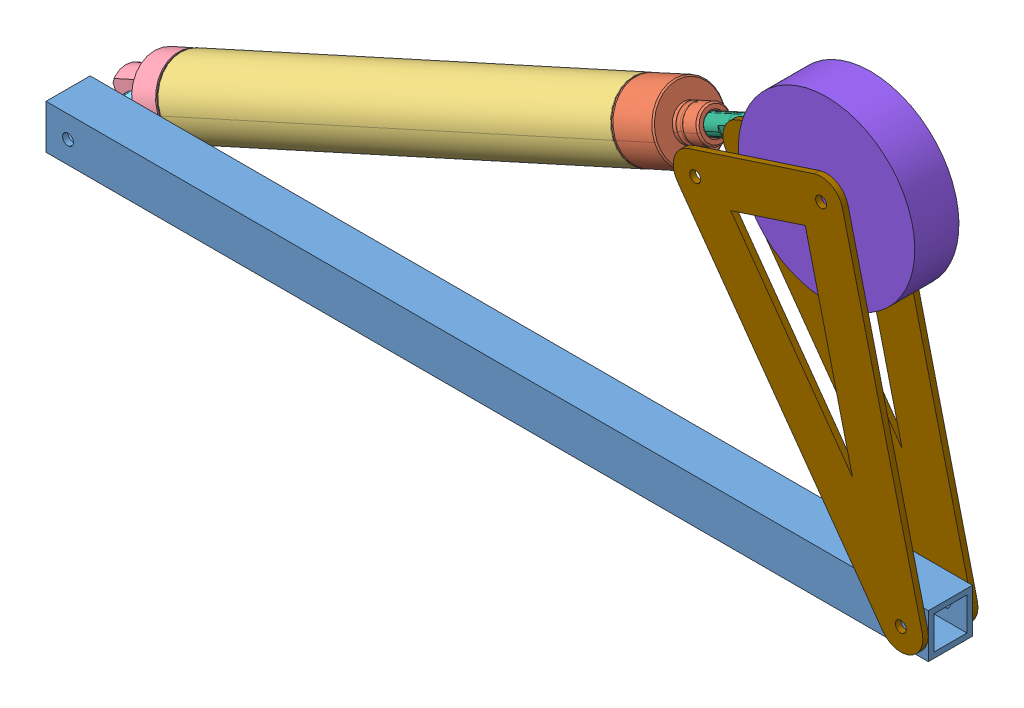
SolidWorks assembly thing, configuration Default. Lengths in mm.
Overall size (529.67 276.12 70.37).
11 component instances, 9 part files, 16 mates.
Components (placement in the parent):
- base-1: base [Default] at (208.2207 241.441 383.4946) size (508 25.4 25.4)
- 1710_DP_NOPISTON-1: 1710_DP_NOPISTON [Default] at (293.7845 389.6661 363.1746) x (-0.910733 -0.412996 0) z (0 0 -1) size (368.43 39.54 39.61)
  - _17R000_0_rod_guide_4-1: _17R000_0_rod_guide_4 [Default] at origin size (47.63 39.54 39.54)
  - _17R_11_30250C_6-1: _17R_11_30250C_6 [Default] at (42.2275 0 0) size (288.92 39.54 39.54)
  - _17P0000_rear_head_8-1: _17P0000_rear_head_8 [Default] at (323.977 0 0) size (44.45 39.54 39.61)
  - _D_358_10-1: _D_358_10 [Default] at (358.902 0 0) x (1 0 0) z (0 0 -1) size (9.53 9.53 25.4)
- _C_1710_DP0000_rod_12-1: _C_1710_DP0000_rod_12 [Default] at (301.3357 393.0904 363.1746) x (-0.910733 -0.412996 0) z (-0.053704 0.118428 -0.991509) size (349.38 38.29 38.29)
- smol-1: smol [Default] at (324.4683 403.5805 363.1746) x (0 0 1) z (-0.412996 0.910733 0) size (9.65 12.19 9.65)
- cirely-1: cirely [Default] at (403.6158 430.2662 383.4946) x (0.029403 -0.999568 0) z (-0.999568 -0.029403 0) size (101.6 25.4 101.6)
- triplate-1: triplate [Default] at (331.1768 406.6226 408.8946) x (0.950644 0.310284 0) z (0.310284 -0.950644 0) size (101.6 3.17 219.15)
- triplate-2: triplate [Default] at (331.1768 406.6226 380.3196) x (0.950644 0.310284 0) z (0.310284 -0.950644 0) size (101.6 3.17 219.15)
Mates (geometry in assembly coordinates):
- Concentric5: concentric: cylinder of base-1 through (-33.0793 241.441 -99.1054) axis (0 0 1) radius 3.175; cylinder of 1710_DP_NOPISTON-1/_D_358_10-1 through (-33.0793 241.441 350.4746) axis (0 0 1) radius 4.7625
- Distance1: distance = 7.62 mm: plane of base-1 through (208.2207 241.441 383.4946) normal (0 0 -1); plane of 1710_DP_NOPISTON-1/_D_358_10-1 through (-33.0793 241.441 375.8746) normal (0 0 1)
- Concentric6: concentric: cylinder of 1710_DP_NOPISTON-1/_17R000_0_rod_guide_4-1 through (250.4109 369.9972 363.1746) axis (0.910733 0.412996 0) radius 5.6134; cylinder of _C_1710_DP0000_rod_12-1 through (6.2792 259.2892 363.1746) axis (0.910733 0.412996 0) radius 5.5499
- LimitDistance1: limit distance = 33.6913 mm: plane of _C_1710_DP0000_rod_12-1 through (324.4683 403.5805 363.1746) normal (0.910733 0.412996 0); plane of 1710_DP_NOPISTON-1/_17R000_0_rod_guide_4-1 through (293.7845 389.6661 363.1746) normal (0.910733 0.412996 0)
- Concentric7: concentric: circle of _C_1710_DP0000_rod_12-1; circle of smol-1
- Coincident8: coincident: plane of _C_1710_DP0000_rod_12-1 through (324.4683 403.5805 363.1746) normal (0.910733 0.412996 0); plane of smol-1 through (324.4683 403.5805 363.1746) normal (-0.910733 -0.412996 0)
- Concentric10: concentric: cylinder of base-1 through (449.5207 241.441 -99.1054) axis (0 0 1) radius 3.175; cylinder of triplate-1 through (449.5207 241.441 412.0696) axis (0 0 -1) radius 3.175
- Coincident14: coincident: plane of base-1 through (208.2207 241.441 408.8946) normal (0 0 1); plane of triplate-1 through (331.1768 406.6226 408.8946) normal (0 0 -1)
- Concentric11: concentric: cylinder of cirely-1 through (403.6158 430.2662 383.4946) axis (0 0 1) radius 3.048; cylinder of triplate-1 through (403.6158 430.2662 412.0696) axis (0 0 -1) radius 3.175
- Concentric12: concentric: cylinder of smol-1 through (331.1768 406.6226 358.3486) axis (0 0 1) radius 3.175; cylinder of triplate-1 through (331.1768 406.6226 412.0696) axis (0 0 -1) radius 3.175
- Coincident15: coincident: plane of cirely-1 through (403.6158 430.2662 408.8946) normal (0 0 1); plane of triplate-1 through (331.1768 406.6226 408.8946) normal (0 0 -1)
- Concentric13: concentric: cylinder of base-1 through (449.5207 241.441 -99.1054) axis (0 0 1) radius 3.175; cylinder of triplate-2 through (449.5207 241.441 383.4946) axis (0 0 -1) radius 3.175
- Concentric14: concentric: cylinder of cirely-1 through (403.6158 430.2662 383.4946) axis (0 0 1) radius 3.048; cylinder of triplate-2 through (403.6158 430.2662 383.4946) axis (0 0 -1) radius 3.175
- Concentric15: concentric: cylinder of smol-1 through (331.1768 406.6226 358.3486) axis (0 0 1) radius 3.175; cylinder of triplate-2 through (331.1768 406.6226 383.4946) axis (0 0 -1) radius 3.175
- Coincident16: coincident: plane of cirely-1 through (403.6158 430.2662 383.4946) normal (0 0 -1); plane of triplate-2 through (331.1768 406.6226 383.4946) normal (0 0 1)
- LimitAngle3: limit planar angle = 2.192476 rad: line of triplate-1 through (320.8529 399.2261 412.0696) axis (0.582401 -0.812901 0); line of base-1 through (462.2207 254.141 408.8946) axis (-1 0 0)
